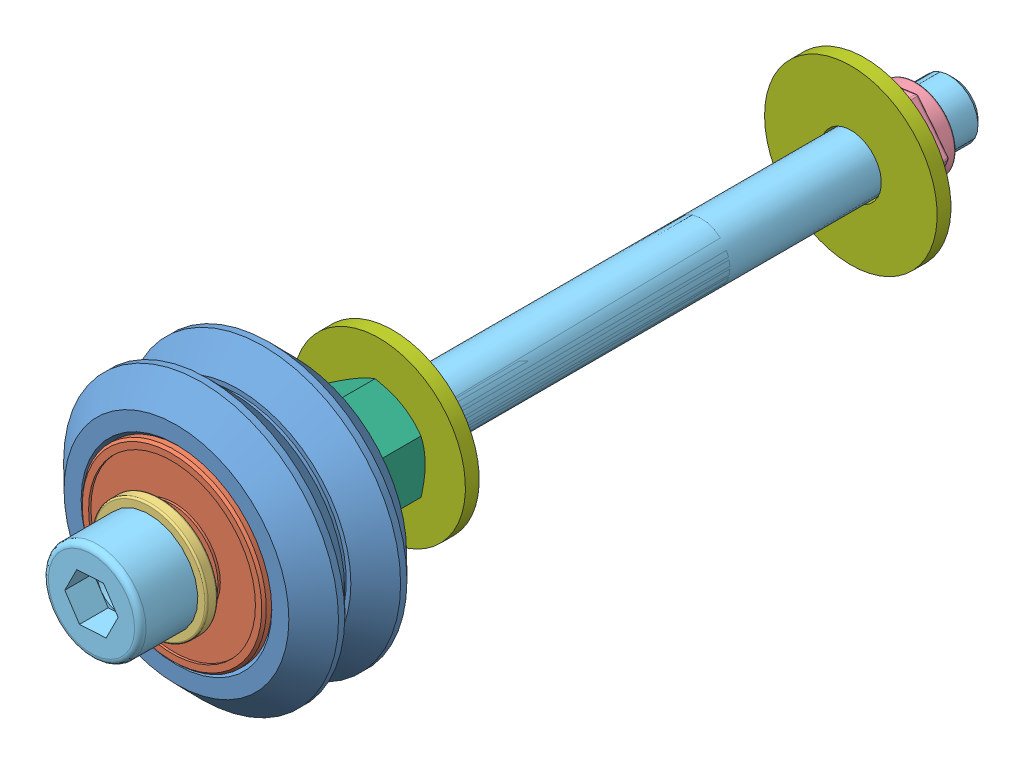
SolidWorks assembly Wheel-GantryCord, configuration Default. Lengths in mm.
Overall size (23.89 23.89 75).
10 component instances, 7 part files, 19 mates.
Components (placement in the parent):
- Delrin Dual V-Wheel-1: Delrin Dual V-Wheel [Default] at (4.1766 13.0717 -11.0846) size (23.89 23.89 10.23)
- Precision Ball Bearing-1: Precision Ball Bearing [Default] at (4.1766 13.0717 -8.0846) x (0 0 -1) z (1 0 0) size (5 16 16)
- Precision Ball Bearing-2: Precision Ball Bearing [Default] at (4.1766 13.0717 -14.0846) x (0 0 -1) z (1 0 0) size (5 16 16)
- 5mm Precision Washer-1: 5mm Precision Washer [Default] at (4.1766 13.0717 -11.5846) x (0 0 1) z (-1 0 0) size (1 10 10)
- Nylon Insert Hex Locknut 5mm-1: Nylon Insert Hex Locknut 5mm [Default] at (4.1766 13.0717 -65.7846) x (-0.927126 0.37475 0) z (0 0 -1) size (7.68 8.82 4.5)
- socket-head-cap-screw-1: socket-head-cap-screw [DIN 912 M5 x 70 --- 22C] at (4.1766 13.0717 1.4154) x (0 0 -1) z (0.057817 -0.998327 0) size (75 8.5 8.5)
- 5mm Precision Washer-2: 5mm Precision Washer [Default] at (4.1766 13.0717 -4.5846) x (0 0 1) z (-0.987639 -0.156746 0) size (1 10 10)
- hex nut style 1 gradeab_din_a2-1: hex nut style 1 gradeab_din_a2 [Hexagon Nut ISO 4032 - M5 - D - C] at (4.1766 13.0717 -18.8846) size (8 9.24 4.7)
- plain washer large_din_a2-1: plain washer large_din_a2 [Washer DIN 9021 - 5.3] at (4.1766 13.0717 -64.5846) x (0 0 1) z (-0.762021 0.647552 0) size (1.2 15 15)
- plain washer large_din_a2-2: plain washer large_din_a2 [Washer DIN 9021 - 5.3] at (4.1766 13.0717 -23.5846) x (0 0 1) z (-0.762021 0.647552 0) size (1.2 15 15)
Mates (geometry in assembly coordinates):
- Coincident1: coincident aligned: plane of Delrin Dual V-Wheel-1 through (4.1766 21.0587 -10.5846) normal (0 0 1); plane of 5mm Precision Washer-1 through (4.1766 13.0717 -10.5846) normal (0 0 1)
- Concentric1: concentric anti-aligned: cylinder of Delrin Dual V-Wheel-1 through (4.1766 13.0717 -5.9696) axis (0 0 1) radius 6.945; cylinder of 5mm Precision Washer-1 through (4.1766 13.0717 -10.5846) axis (0 0 -1) radius 2.5
- Coincident2: coincident anti-aligned: plane of Delrin Dual V-Wheel-1 through (4.1766 21.0587 -10.5846) normal (0 0 1); plane of Precision Ball Bearing-1 through (4.1766 13.0717 -10.5846) normal (0 0 -1)
- Concentric2: concentric aligned: cylinder of Delrin Dual V-Wheel-1 through (4.1766 13.0717 -5.9696) axis (0 0 1) radius 7.987; cylinder of Precision Ball Bearing-1 through (4.1766 13.0717 -10.5846) axis (0 0 1) radius 8
- Coincident3: coincident anti-aligned: plane of Delrin Dual V-Wheel-1 through (4.1766 21.0587 -11.5846) normal (0 0 -1); plane of Precision Ball Bearing-2 through (4.1766 13.0717 -11.5846) normal (0 0 1)
- Concentric3: concentric aligned: cylinder of Delrin Dual V-Wheel-1 through (4.1766 13.0717 -5.9696) axis (0 0 1) radius 7.987; cylinder of Precision Ball Bearing-2 through (4.1766 13.0717 -16.5846) axis (0 0 1) radius 8
- Concentric4: concentric aligned: cylinder of Precision Ball Bearing-2 through (4.1766 13.0717 -11.5846) axis (0 0 -1) radius 2.5; cylinder of Nylon Insert Hex Locknut 5mm-1 through (4.1766 13.0717 -65.7846) axis (0 0 -1) radius 2.5
- Concentric5: concentric anti-aligned: cylinder of Precision Ball Bearing-2 through (4.1766 13.0717 -11.5846) axis (0 0 -1) radius 2.5; cylinder of socket-head-cap-screw-1 through (4.1766 13.0717 33.1654) axis (0 0 1) radius 2.5
- Concentric6: concentric anti-aligned: cylinder of socket-head-cap-screw-1 through (4.1766 13.0717 33.1654) axis (0 0 1) radius 2.5; cylinder of 5mm Precision Washer-2 through (4.1766 13.0717 -3.5846) axis (0 0 -1) radius 2.5
- Coincident4: coincident anti-aligned: plane of socket-head-cap-screw-1 through (7.5249 15.6892 -0.5846) normal (0 0 -1); plane of 5mm Precision Washer-2 through (4.1766 13.0717 -0.5846) normal (0 0 1)
- Distance6: distance = 3.44 mm aligned: plane of Nylon Insert Hex Locknut 5mm-1 through (4.1766 13.0717 -70.1446) normal (0 0 -1); plane of socket-head-cap-screw-1 through (6.2281 13.1905 -73.5846) normal (0 0 -1)
- Concentric9: concentric aligned: cylinder of socket-head-cap-screw-1 through (4.1766 13.0717 33.1654) axis (0 0 1) radius 2.5; cylinder of hex nut style 1 gradeab_din_a2-1 through (4.1766 13.0717 -23.5846) axis (0 0 1) radius 2.1
- Distance2: distance = 20 mm aligned: plane of hex nut style 1 gradeab_din_a2-1 through (4.1766 17.6905 -23.5846) normal (0 0 -1); plane of socket-head-cap-screw-1 through (8.4195 13.3174 -3.5846) normal (0 0 -1)
- Distance5: distance = 7.5 mm anti-aligned: plane of Delrin Dual V-Wheel-1 through (4.1766 13.0717 -11.0846) normal (0 0 1); plane of socket-head-cap-screw-1 through (8.4195 13.3174 -3.5846) normal (0 0 -1)
- Coincident7: coincident anti-aligned: plane of socket-head-cap-screw-1 through (8.4195 13.3174 -3.5846) normal (0 0 -1); plane of 5mm Precision Washer-2 through (4.1766 13.0717 -3.5846) normal (0 0 1)
- Concentric11: concentric anti-aligned: cylinder of socket-head-cap-screw-1 through (4.1766 13.0717 33.1654) axis (0 0 1) radius 2.5; cylinder of plain washer large_din_a2-1 through (4.1766 13.0717 -99.5096) axis (0 0 -1) radius 2.65
- Concentric12: concentric anti-aligned: cylinder of socket-head-cap-screw-1 through (4.1766 13.0717 33.1654) axis (0 0 1) radius 2.5; cylinder of plain washer large_din_a2-2 through (4.1766 13.0717 -58.5096) axis (0 0 -1) radius 2.65
- Coincident8: coincident anti-aligned: plane of hex nut style 1 gradeab_din_a2-1 through (4.1766 17.6905 -23.5846) normal (0 0 -1); plane of plain washer large_din_a2-2 through (5.8926 15.0911 -23.5846) normal (0 0 1)
- Coincident9: coincident anti-aligned: plane of Nylon Insert Hex Locknut 5mm-1 through (4.1766 13.0717 -65.7846) normal (0 0 1); plane of plain washer large_din_a2-1 through (9.0332 18.7869 -65.7846) normal (0 0 -1)
